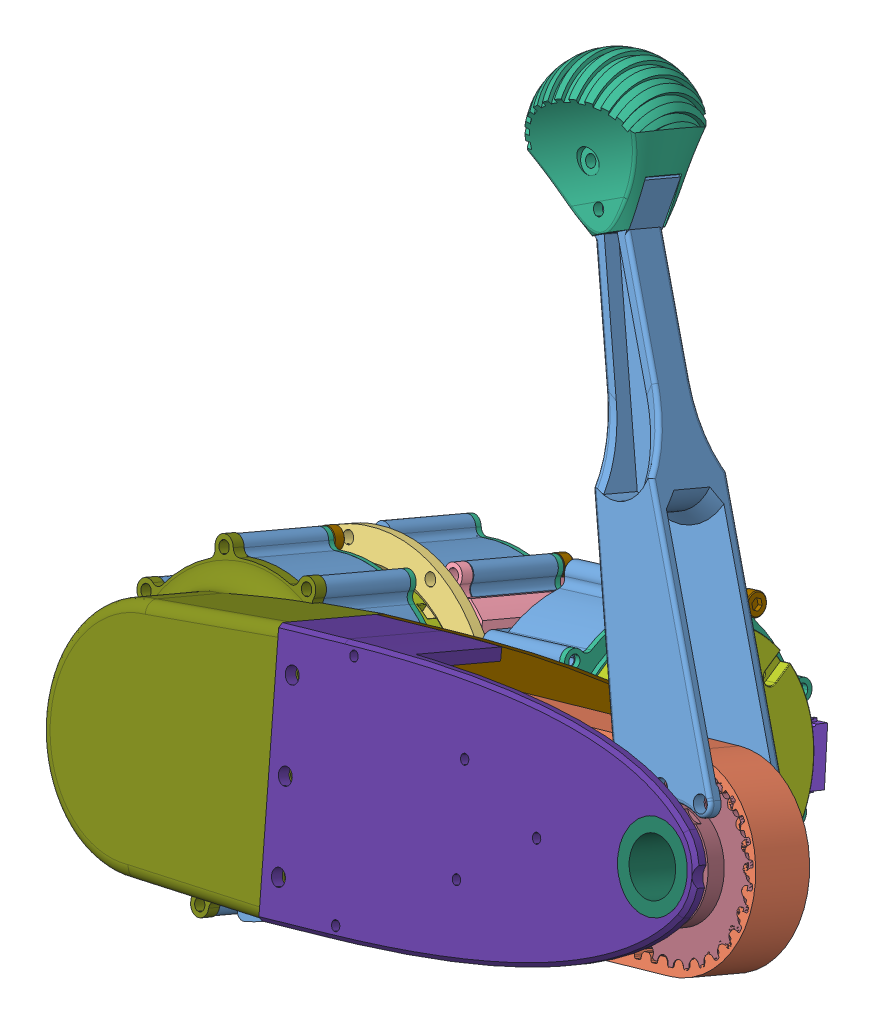
SolidWorks assembly 机械腿装配体, configuration 默认. Lengths in mm.
Overall size (235.81 267.44 159.84).
76 component instances, 24 part files, 46 mates.
Components (placement in the parent):
- CyberGearmotor.stp-1: CyberGearmotor.stp [默认] at (-32.9062 325.199 163.8526) x (0.625011 -0.709591 0.325334) z (0.103003 -0.338154 -0.935437) size (96.28 96.17 36.5)
  - ASM0002_ASM_1_ASM.stp-1: ASM0002_ASM_1_ASM.stp [默认] at origin size (96.28 96.17 36.5)
    - ASM0002_ASM_1_ASM_1_ASM.stp-1: ASM0002_ASM_1_ASM_1_ASM.stp [默认] at origin size (96.28 96.17 36.5)
      - 0714_ASM_1_ASM_1_ASM_1_ASM.stp-1: 0714_ASM_1_ASM_1_ASM_1_ASM.stp [默认] at origin size (96.28 96.17 36.5)
        - 3_1_02_067_0003_ASM_ASM_1_ASM_1_ASM.stp-1: 3_1_02_067_0003_ASM_ASM_1_ASM_1_ASM.stp [默认] at origin size (96.28 96.17 36.5)
          - 3_1_02_067_0003_ASM_1_ASM_1_ASM_ASM.stp-1: 3_1_02_067_0003_ASM_1_ASM_1_ASM_ASM.stp [默认] at origin size (96.28 96.17 36.5)
            - 1_1_06_EB673-504_1_1_1_1_1.stp-1: 1_1_06_EB673-504_1_1_1_1_1.stp [默认] at (39.8324 39.833 -22) size (79.19 78.95 25.5)
            - 1_2_04_670601_1_1_1_1_1.stp-1: 1_2_04_670601_1_1_1_1_1.stp [默认] at (93.9161 79.9966 -44) size (37 37 4)
            - 1_1_02_EB671-500_1_1_1_1_1.stp-1: 1_1_02_EB671-500_1_1_1_1_1.stp [默认] at (93.9161 79.9966 -44.4) x (-0.960973 0.276644 0) z (0 0 1) size (33 33 8.5)
            - 1_2_04_694000_1_1_1_1_1.stp-1: 1_2_04_694000_1_1_1_1_1.stp [默认] at (93.9161 79.9966 -44.5) size (11 11 4)
            - 1_2_06_000213_1_1_1_1_1.stp-1: 1_2_06_000213_1_1_1_1_1.stp [默认] at (93.9161 79.9966 -45.5) size (38.8 36.2 1.5)
            - 1_1_31_QT-642_1_1_1_1_1.stp-1: 1_1_31_QT-642_1_1_1_1_1.stp [默认] at (93.9161 79.9966 -22) x (-0.970555 -0.24088 0) z (0 0 -1) size (79.5 79.36 6)
            - 1_1_06_EB673-502_1_1_1_1_1.stp-1: 1_1_06_EB673-502_1_1_1_1_1.stp [默认] at (93.9161 79.9966 -13) x (-0.515958 -0.856614 0) z (0 0 -1) size (63 63 8)
          - 0518_ASM_2_ASM_1_ASM_1_ASM_1_AS_ASM.stp-1: 0518_ASM_2_ASM_1_ASM_1_ASM_1_AS_ASM.stp [默认] at (93.9161 79.9966 -17.235) x (0.235897 -0.971778 0) z (0 0 1) size (15.5 11.3 5.2)
            - 12345_ASM_1_ASM_2_ASM_1_ASM_1_A_ASM.stp-1: 12345_ASM_1_ASM_2_ASM_1_ASM_1_A_ASM.stp [默认] at origin size (15.5 11.3 5.2)
              - DUANZI_1_3_1_1_1_1_1_1.stp-1: DUANZI_1_3_1_1_1_1_1_1.stp [默认] at (-0.1798 16.5474 0.4329) x (0 0 -1) z (0 1 0) size (5.2 15.5 11.3)
      - LUODING_1_1.stp-1: LUODING_1_1.stp [默认] at (119.9375 52.9941 -20.5) x (-1 0 0) z (0 1 0) size (5.68 3 5.68)
      - LUODING_1_1.stp-2: LUODING_1_1.stp [默认] at (104.2902 116.0331 -20.5) x (-1 0 0) z (0 1 0) size (5.68 3 5.68)
      - LUODING_1_1.stp-3: LUODING_1_1.stp [默认] at (57.5205 70.9626 -20.5) x (-1 0 0) z (0 1 0) size (5.68 3 5.68)
  - 0411-2_4_1_3_1.stp-1: 0411-2_4_1_3_1.stp [默认] at (93.9161 79.9964 -17.5) x (0.235904 -0.971776 0) z (0 0 1) size (58 56.68 1.62)
- 带轮-1: 带轮 [默认] at (-43.0537 231.9338 268.6088) x (-0.773277 0.564305 -0.28914) z (0.103003 -0.338154 -0.935437) size (43.22 43.22 15)
- 带轮挡边-1: 带轮挡边 [默认] at (-41.5159 226.8587 254.5775) x (-0.77368 0.56382 -0.289009) z (0.103003 -0.338154 -0.935437) size (50 50 4)
- 带轮挡边-2: 带轮挡边 [默认] at (-43.4729 233.2836 272.3508) x (-0.154553 -0.934458 0.320782) z (0.103003 -0.338154 -0.935437) size (50 50 4)
- 膝关节带轮-1: 膝关节带轮 [默认] at (87.8678 264.231 271.3497) x (-0.849589 -0.51899 0.094061) z (0.103003 -0.338154 -0.935437) size (43.22 43.22 23)
- 轴承-1: 轴承 [默认] at (108.6723 269.1151 252.0981) x (-0.628078 -0.751354 0.20245) z (-0.103003 0.338154 0.935437) size (23 23 4)
- 轴承-2: 轴承 [默认] at (106.7153 275.54 269.8714) x (0.986125 -0.08837 0.14053) z (-0.103003 0.338154 0.935437) size (23 23 4)
- 膝关节转轴-1: 膝关节转轴 [默认] at (108.9298 268.2697 249.7595) x (-0.975627 0.148845 -0.161235) z (-0.103003 0.338154 0.935437) size (21 21 29)
- 大腿根部SLDPRT-3: 大腿根部SLDPRT [默认] at (-114.7317 234.0313 236.4395) x (-0.869822 -0.486803 0.080198) z (-0.103003 0.338154 0.935437) size (94.61 80.08 30.19)
- 大腿前部-1: 大腿前部 [默认] at (32.2959 248.9567 279.3042) x (0.25876 -0.89895 0.353457) z (0.960434 0.278461 0.005094) size (62 27.01 128.98)
- 大腿前部盖子-1: 大腿前部盖子 [默认] at (31.2591 253.1493 245.6039) x (-0.25876 0.89895 -0.353457) z (0.960434 0.278461 0.005094) size (62 3.5 129)
- 小腿2-1: 小腿2 [默认] at (74.1718 322.5647 235.3916) x (-0.51729 0.785048 -0.34075) z (0.849589 0.51899 -0.094061) size (141.69 21.45 28.63)
- 5m同步带1-1: 5m同步带1 [默认] at (106.5885 272.5591 262.3829) x (-0.103003 0.338154 0.935437) z (0.960434 0.278461 0.005094) size (15 46.9 201.91)
- 连接盘-1: 连接盘 [默认] at (-37.4901 211.9018 211.7872) x (-0.928292 -0.370496 0.031715) z (-0.3573 0.865092 -0.352068) size (80.5 13.5 80.5)
- CyberGearmotor.stp-2: CyberGearmotor.stp [默认] at (47.9911 286 142.5663) x (-0.002703 -0.940531 0.339698) z (0.103003 -0.338154 -0.935437) size (96.28 96.17 36.5)
  - ASM0002_ASM_1_ASM.stp-1: ASM0002_ASM_1_ASM.stp [默认] at origin size (96.28 96.17 36.5)
    - ASM0002_ASM_1_ASM_1_ASM.stp-1: ASM0002_ASM_1_ASM_1_ASM.stp [默认] at origin size (96.28 96.17 36.5)
      - 0714_ASM_1_ASM_1_ASM_1_ASM.stp-1: 0714_ASM_1_ASM_1_ASM_1_ASM.stp [默认] at origin size (96.28 96.17 36.5)
        - 3_1_02_067_0003_ASM_ASM_1_ASM_1_ASM.stp-1: 3_1_02_067_0003_ASM_ASM_1_ASM_1_ASM.stp [默认] at origin size (96.28 96.17 36.5)
          - 3_1_02_067_0003_ASM_1_ASM_1_ASM_ASM.stp-1: 3_1_02_067_0003_ASM_1_ASM_1_ASM_ASM.stp [默认] at origin size (96.28 96.17 36.5)
            - 1_1_06_EB673-504_1_1_1_1_1.stp-1: 1_1_06_EB673-504_1_1_1_1_1.stp [默认] at (39.8324 39.833 -22) size (79.19 78.95 25.5)
            - 1_2_04_670601_1_1_1_1_1.stp-1: 1_2_04_670601_1_1_1_1_1.stp [默认] at (93.9161 79.9966 -44) size (37 37 4)
            - 1_1_02_EB671-500_1_1_1_1_1.stp-1: 1_1_02_EB671-500_1_1_1_1_1.stp [默认] at (93.9161 79.9966 -44.4) x (-0.960973 0.276644 0) z (0 0 1) size (33 33 8.5)
            - 1_2_04_694000_1_1_1_1_1.stp-1: 1_2_04_694000_1_1_1_1_1.stp [默认] at (93.9161 79.9966 -44.5) size (11 11 4)
            - 1_2_06_000213_1_1_1_1_1.stp-1: 1_2_06_000213_1_1_1_1_1.stp [默认] at (93.9161 79.9966 -45.5) size (38.8 36.2 1.5)
            - 1_1_31_QT-642_1_1_1_1_1.stp-1: 1_1_31_QT-642_1_1_1_1_1.stp [默认] at (93.9161 79.9966 -22) x (-0.970555 -0.24088 0) z (0 0 -1) size (79.5 79.36 6)
            - 1_1_06_EB673-502_1_1_1_1_1.stp-1: 1_1_06_EB673-502_1_1_1_1_1.stp [默认] at (93.9161 79.9966 -13) x (-0.515958 -0.856614 0) z (0 0 -1) size (63 63 8)
          - 0518_ASM_2_ASM_1_ASM_1_ASM_1_AS_ASM.stp-1: 0518_ASM_2_ASM_1_ASM_1_ASM_1_AS_ASM.stp [默认] at (93.9161 79.9966 -17.235) x (0.235897 -0.971778 0) z (0 0 1) size (15.5 11.3 5.2)
            - 12345_ASM_1_ASM_2_ASM_1_ASM_1_A_ASM.stp-1: 12345_ASM_1_ASM_2_ASM_1_ASM_1_A_ASM.stp [默认] at origin size (15.5 11.3 5.2)
              - DUANZI_1_3_1_1_1_1_1_1.stp-1: DUANZI_1_3_1_1_1_1_1_1.stp [默认] at (-0.1798 16.5474 0.4329) x (0 0 -1) z (0 1 0) size (5.2 15.5 11.3)
      - LUODING_1_1.stp-1: LUODING_1_1.stp [默认] at (119.9375 52.9941 -20.5) x (-1 0 0) z (0 1 0) size (5.68 3 5.68)
      - LUODING_1_1.stp-2: LUODING_1_1.stp [默认] at (104.2902 116.0331 -20.5) x (-1 0 0) z (0 1 0) size (5.68 3 5.68)
      - LUODING_1_1.stp-3: LUODING_1_1.stp [默认] at (57.5205 70.9626 -20.5) x (-1 0 0) z (0 1 0) size (5.68 3 5.68)
  - 0411-2_4_1_3_1.stp-1: 0411-2_4_1_3_1.stp [默认] at (93.9161 79.9964 -17.5) x (0.235904 -0.971776 0) z (0 0 1) size (58 56.68 1.62)
- 肩关节连接器-1: 肩关节连接器 [默认] at (-3.9141 154.2094 236.5535) x (-0.002729 -0.940532 0.339695) z (0.994677 0.032437 0.097801) size (67.92 36.71 40.7)
- CyberGearmotor.stp-3: CyberGearmotor.stp [默认] at (56.3683 218.9179 320.1116) x (0.161386 -0.529819 -0.832614) z (0.956605 0.291387 0) size (96.28 96.17 36.5)
  - ASM0002_ASM_1_ASM.stp-1: ASM0002_ASM_1_ASM.stp [默认] at origin size (96.28 96.17 36.5)
    - ASM0002_ASM_1_ASM_1_ASM.stp-1: ASM0002_ASM_1_ASM_1_ASM.stp [默认] at origin size (96.28 96.17 36.5)
      - 0714_ASM_1_ASM_1_ASM_1_ASM.stp-1: 0714_ASM_1_ASM_1_ASM_1_ASM.stp [默认] at origin size (96.28 96.17 36.5)
        - 3_1_02_067_0003_ASM_ASM_1_ASM_1_ASM.stp-1: 3_1_02_067_0003_ASM_ASM_1_ASM_1_ASM.stp [默认] at origin size (96.28 96.17 36.5)
          - 3_1_02_067_0003_ASM_1_ASM_1_ASM_ASM.stp-1: 3_1_02_067_0003_ASM_1_ASM_1_ASM_ASM.stp [默认] at origin size (96.28 96.17 36.5)
            - 1_1_06_EB673-504_1_1_1_1_1.stp-1: 1_1_06_EB673-504_1_1_1_1_1.stp [默认] at (39.8324 39.833 -22) size (79.19 78.95 25.5)
            - 1_2_04_670601_1_1_1_1_1.stp-1: 1_2_04_670601_1_1_1_1_1.stp [默认] at (93.9161 79.9966 -44) size (37 37 4)
            - 1_1_02_EB671-500_1_1_1_1_1.stp-1: 1_1_02_EB671-500_1_1_1_1_1.stp [默认] at (93.9161 79.9966 -44.4) x (-0.960973 0.276644 0) z (0 0 1) size (33 33 8.5)
            - 1_2_04_694000_1_1_1_1_1.stp-1: 1_2_04_694000_1_1_1_1_1.stp [默认] at (93.9161 79.9966 -44.5) size (11 11 4)
            - 1_2_06_000213_1_1_1_1_1.stp-1: 1_2_06_000213_1_1_1_1_1.stp [默认] at (93.9161 79.9966 -45.5) size (38.8 36.2 1.5)
            - 1_1_31_QT-642_1_1_1_1_1.stp-1: 1_1_31_QT-642_1_1_1_1_1.stp [默认] at (93.9161 79.9966 -22) x (-0.970555 -0.24088 0) z (0 0 -1) size (79.5 79.36 6)
            - 1_1_06_EB673-502_1_1_1_1_1.stp-1: 1_1_06_EB673-502_1_1_1_1_1.stp [默认] at (93.9161 79.9966 -13) x (-0.515958 -0.856614 0) z (0 0 -1) size (63 63 8)
          - 0518_ASM_2_ASM_1_ASM_1_ASM_1_AS_ASM.stp-1: 0518_ASM_2_ASM_1_ASM_1_ASM_1_AS_ASM.stp [默认] at (93.9161 79.9966 -17.235) x (0.235897 -0.971778 0) z (0 0 1) size (15.5 11.3 5.2)
            - 12345_ASM_1_ASM_2_ASM_1_ASM_1_A_ASM.stp-1: 12345_ASM_1_ASM_2_ASM_1_ASM_1_A_ASM.stp [默认] at origin size (15.5 11.3 5.2)
              - DUANZI_1_3_1_1_1_1_1_1.stp-1: DUANZI_1_3_1_1_1_1_1_1.stp [默认] at (-0.1798 16.5474 0.4329) x (0 0 -1) z (0 1 0) size (5.2 15.5 11.3)
      - LUODING_1_1.stp-1: LUODING_1_1.stp [默认] at (119.9375 52.9941 -20.5) x (-1 0 0) z (0 1 0) size (5.68 3 5.68)
      - LUODING_1_1.stp-2: LUODING_1_1.stp [默认] at (104.2902 116.0331 -20.5) x (-1 0 0) z (0 1 0) size (5.68 3 5.68)
      - LUODING_1_1.stp-3: LUODING_1_1.stp [默认] at (57.5205 70.9626 -20.5) x (-1 0 0) z (0 1 0) size (5.68 3 5.68)
  - 0411-2_4_1_3_1.stp-1: 0411-2_4_1_3_1.stp [默认] at (93.9161 79.9964 -17.5) x (0.235904 -0.971776 0) z (0 0 1) size (58 56.68 1.62)
- 大腿根部线束限位扣-1: 大腿根部线束限位扣 [默认] at (9.8494 240.149 247.9459) x (-0.25876 0.89895 -0.353457) z (-0.960434 -0.278461 -0.005094) size (22 6 10)
- 狗jio-1: 狗jio [默认] at (30.4631 389.807 211.6162) x (0.849589 0.51899 -0.094061) z (0.103003 -0.338154 -0.935437) size (38.01 39.33 33.29)
Mates (geometry in assembly coordinates):
- 同心1: concentric aligned: cylinder of CyberGearmotor.stp-1/ASM0002_ASM_1_ASM.stp-1/ASM0002_ASM_1_ASM_1_ASM.stp-1/0714_ASM_1_ASM_1_ASM_1_ASM.stp-1/3_1_02_067_0003_ASM_ASM_1_ASM_1_ASM.stp-1/3_1_02_067_0003_ASM_1_ASM_1_ASM_ASM.stp-1/1_1_02_EB671-500_1_1_1_1_1.stp-1 through (-40.6815 224.1196 247.0004) axis (-0.103003 0.338154 0.935437) radius 16.5; cylinder of 带轮挡边-1 through (-41.1039 225.506 250.8357) axis (-0.103003 0.338154 0.935437) radius 25
- 重合1: coincident anti-aligned: plane of CyberGearmotor.stp-1/ASM0002_ASM_1_ASM.stp-1/ASM0002_ASM_1_ASM_1_ASM.stp-1/0714_ASM_1_ASM_1_ASM_1_ASM.stp-1/3_1_02_067_0003_ASM_ASM_1_ASM_1_ASM.stp-1/3_1_02_067_0003_ASM_1_ASM_1_ASM_ASM.stp-1/1_1_02_EB671-500_1_1_1_1_1.stp-1 through (-41.1039 225.506 250.8357) normal (-0.103003 0.338154 0.935437); plane of 带轮挡边-1 through (-41.1039 225.506 250.8357) normal (0.103003 -0.338154 -0.935437)
- 重合4: coincident anti-aligned: plane of 带轮-1 through (-30.3993 244.2236 249.5242) normal (0.103003 -0.338154 -0.935437); plane of 带轮挡边-1 through (-41.5159 226.8587 254.5775) normal (-0.103003 0.338154 0.935437)
- 同心12: concentric aligned: cylinder of CyberGearmotor.stp-1/ASM0002_ASM_1_ASM.stp-1/ASM0002_ASM_1_ASM_1_ASM.stp-1/0714_ASM_1_ASM_1_ASM_1_ASM.stp-1/3_1_02_067_0003_ASM_ASM_1_ASM_1_ASM.stp-1/3_1_02_067_0003_ASM_1_ASM_1_ASM_ASM.stp-1/1_1_02_EB671-500_1_1_1_1_1.stp-1 through (-40.6815 224.1196 247.0004) axis (-0.103003 0.338154 0.935437) radius 16.5; cylinder of 带轮挡边-2 through (-43.0609 231.931 268.609) axis (-0.103003 0.338154 0.935437) radius 25
- 重合5: coincident anti-aligned: plane of 带轮-1 through (-31.9444 249.2959 263.5558) normal (-0.103003 0.338154 0.935437); plane of 带轮挡边-2 through (-43.0609 231.931 268.609) normal (0.103003 -0.338154 -0.935437)
- 同心20: concentric aligned: cylinder of 轴承-1 through (108.2603 270.4677 255.8398) axis (0.103003 -0.338154 -0.935437) radius 8.5; cylinder of 膝关节转轴-1 through (106.0457 277.738 275.9517) axis (0.103003 -0.338154 -0.935437) radius 8.5
- 重合12: coincident anti-aligned: plane of CyberGearmotor.stp-1/ASM0002_ASM_1_ASM.stp-1/ASM0002_ASM_1_ASM_1_ASM.stp-1/0714_ASM_1_ASM_1_ASM_1_ASM.stp-1/3_1_02_067_0003_ASM_ASM_1_ASM_1_ASM.stp-1/3_1_02_067_0003_ASM_1_ASM_1_ASM_ASM.stp-1/1_1_06_EB673-504_1_1_1_1_1.stp-1 through (-39.9814 224.5982 248.0804) normal (-0.103003 0.338154 0.935437); plane of 大腿根部SLDPRT-3 through (-114.7317 234.0313 236.4395) normal (0.103003 -0.338154 -0.935437)
- 重合17: coincident anti-aligned: plane of 大腿根部SLDPRT-3 through (-3.7839 276.1352 262.2995) normal (-0.103003 0.338154 0.935437); plane of 大腿前部-1 through (32.6049 247.9422 276.4979) normal (0.103003 -0.338154 -0.935437)
- 重合18: coincident anti-aligned: plane of 大腿根部SLDPRT-3 through (-10.6072 264.2204 236.9917) normal (0.960434 0.278461 0.005094); plane of 大腿前部-1 through (-3.0951 237.5916 276.3086) normal (-0.960434 -0.278461 -0.005094)
- 重合21: coincident anti-aligned: plane of 大腿根部SLDPRT-3 through (14.4721 213.244 258.1809) normal (0.25876 -0.89895 0.353457); plane of 大腿前部-1 through (40.2588 221.8245 261.1256) normal (-0.25876 0.89895 -0.353457)
- 同心32: concentric anti-aligned: cylinder of 膝关节转轴-1 through (106.0457 277.738 275.9517) axis (0.103003 -0.338154 -0.935437) radius 8.5; cylinder of 大腿前部-1 through (106.2518 277.0617 274.0809) axis (-0.103003 0.338154 0.935437) radius 8.5
- 重合23: coincident aligned: plane of 膝关节转轴-1 through (105.9427 278.0762 276.8872) normal (-0.103003 0.338154 0.935437); plane of 大腿前部-1 through (32.2959 248.9567 279.3042) normal (-0.103003 0.338154 0.935437)
- 重合32: coincident anti-aligned: plane of 带轮挡边-1 through (-41.5159 226.8587 254.5775) normal (-0.103003 0.338154 0.935437); plane of 5m同步带1-1 through (102.2769 287.6855 248.4224) normal (0.103003 -0.338154 -0.935437)
- 同心44: concentric aligned: cylinder of 带轮挡边-1 through (-41.1039 225.506 250.8357) axis (-0.103003 0.338154 0.935437) radius 25; cylinder of 5m同步带1-1 through (-42.2884 229.3948 261.5932) axis (-0.103003 0.338154 0.935437) radius 23.448
- 同心47: concentric anti-aligned: cylinder of 膝关节带轮-1 through (108.3118 270.2986 255.3721) axis (-0.103003 0.338154 0.935437) radius 10.5; cylinder of 膝关节转轴-1 through (106.0457 277.738 275.9517) axis (0.103003 -0.338154 -0.935437) radius 8.5
- 重合38: coincident anti-aligned: plane of 带轮-1 through (-30.3993 244.2236 249.5242) normal (0.103003 -0.338154 -0.935437); plane of 带轮挡边-1 through (-41.5159 226.8587 254.5775) normal (-0.103003 0.338154 0.935437)
- 重合39: coincident aligned: plane of 带轮-1 through (-31.9444 249.2959 263.5558) normal (-0.103003 0.338154 0.935437); plane of 膝关节带轮-1 through (93.6077 290.474 262.495) normal (-0.103003 0.338154 0.935437)
- 重合41: coincident anti-aligned: plane of 膝关节带轮-1 through (108.2333 270.5153 255.8197) normal (0.103003 -0.338154 -0.935437); plane of 轴承-1 through (108.2603 270.4677 255.8398) normal (-0.103003 0.338154 0.935437)
- 重合42: coincident anti-aligned: plane of 膝关节带轮-1 through (93.6077 290.474 262.495) normal (-0.103003 0.338154 0.935437); plane of 小腿2-1 through (72.8843 326.7916 247.0846) normal (0.103003 -0.338154 -0.935437)
- 同心50: concentric aligned: cylinder of 膝关节带轮-1 through (112.0714 285.0521 250.4528) axis (0.103003 -0.338154 -0.935437) radius 1.65; cylinder of 小腿2-1 through (107.2302 300.9454 294.4183) axis (0.103003 -0.338154 -0.935437) radius 2.1
- 同心51: concentric aligned: cylinder of 膝关节带轮-1 through (100.0352 282.8594 249.9201) axis (0.103003 -0.338154 -0.935437) radius 1.65; cylinder of 小腿2-1 through (95.194 298.7526 293.8857) axis (0.103003 -0.338154 -0.935437) radius 2.1
- 同心53: concentric aligned: circle of 轴承-2; cylinder of 膝关节转轴-1 through (108.4148 269.9605 254.4367) axis (-0.103003 0.338154 0.935437) radius 7
- 重合44: coincident anti-aligned: plane of 大腿根部SLDPRT-3 through (-1.3118 268.0195 239.849) normal (0.103003 -0.338154 -0.935437); plane of 大腿前部盖子-1 through (30.9501 254.1637 248.4102) normal (-0.103003 0.338154 0.935437)
- 同心54: concentric anti-aligned: cylinder of 大腿根部SLDPRT-3 through (-5.7904 265.0304 266.0928) axis (-0.103003 0.338154 0.935437) radius 1.65; cylinder of 大腿前部盖子-1 through (-3.3183 256.9147 243.6423) axis (0.103003 -0.338154 -0.935437) radius 2.1
- 同心55: concentric anti-aligned: cylinder of 大腿根部SLDPRT-3 through (5.0776 227.2745 280.938) axis (-0.103003 0.338154 0.935437) radius 1.65; cylinder of 大腿前部盖子-1 through (7.5496 219.1588 258.4875) axis (0.103003 -0.338154 -0.935437) radius 2.1
- 重合45: coincident anti-aligned: plane of CyberGearmotor.stp-1/ASM0002_ASM_1_ASM.stp-1/ASM0002_ASM_1_ASM_1_ASM.stp-1/0714_ASM_1_ASM_1_ASM_1_ASM.stp-1/3_1_02_067_0003_ASM_ASM_1_ASM_1_ASM.stp-1/3_1_02_067_0003_ASM_1_ASM_1_ASM_ASM.stp-1/1_1_06_EB673-502_1_1_1_1_1.stp-1 through (-37.3442 213.1634 216.6923) normal (0.103003 -0.338154 -0.935437); plane of 连接盘-1 through (-38.0051 213.5926 216.4644) normal (-0.103003 0.338154 0.935437)
- 同心56: concentric aligned: cylinder of CyberGearmotor.stp-1/ASM0002_ASM_1_ASM.stp-1/ASM0002_ASM_1_ASM_1_ASM.stp-1/0714_ASM_1_ASM_1_ASM_1_ASM.stp-1/3_1_02_067_0003_ASM_ASM_1_ASM_1_ASM.stp-1/3_1_02_067_0003_ASM_1_ASM_1_ASM_ASM.stp-1/1_1_06_EB673-502_1_1_1_1_1.stp-1 through (-38.1683 215.8686 224.1758) axis (0.103003 -0.338154 -0.935437) radius 31.5; cylinder of 连接盘-1 through (-37.3442 213.1634 216.6923) axis (0.103003 -0.338154 -0.935437) radius 40.25
- 同心57: concentric aligned: cylinder of CyberGearmotor.stp-1/ASM0002_ASM_1_ASM.stp-1/ASM0002_ASM_1_ASM_1_ASM.stp-1/0714_ASM_1_ASM_1_ASM_1_ASM.stp-1/3_1_02_067_0003_ASM_ASM_1_ASM_1_ASM.stp-1/3_1_02_067_0003_ASM_1_ASM_1_ASM_ASM.stp-1/1_1_31_QT-642_1_1_1_1_1.stp-1 through (-28.5595 250.441 213.2706) axis (0.103003 -0.338154 -0.935437) radius 1.55; cylinder of 连接盘-1 through (-27.684 247.5667 205.3194) axis (0.103003 -0.338154 -0.935437) radius 1.6
- 同心61: concentric aligned: cylinder of CyberGearmotor.stp-1/ASM0002_ASM_1_ASM.stp-1/ASM0002_ASM_1_ASM_1_ASM.stp-1/0714_ASM_1_ASM_1_ASM_1_ASM.stp-1/3_1_02_067_0003_ASM_ASM_1_ASM_1_ASM.stp-1/3_1_02_067_0003_ASM_1_ASM_1_ASM_ASM.stp-1/1_1_06_EB673-502_1_1_1_1_1.stp-1 through (-38.1683 215.8686 224.1758) axis (0.103003 -0.338154 -0.935437) radius 31.5; cylinder of CyberGearmotor.stp-2/ASM0002_ASM_1_ASM.stp-1/ASM0002_ASM_1_ASM_1_ASM.stp-1/0714_ASM_1_ASM_1_ASM_1_ASM.stp-1/3_1_02_067_0003_ASM_ASM_1_ASM_1_ASM.stp-1/3_1_02_067_0003_ASM_1_ASM_1_ASM_ASM.stp-1/1_1_06_EB673-502_1_1_1_1_1.stp-1 through (-33.8936 201.8353 185.3551) axis (0.103003 -0.338154 -0.935437) radius 31.5
- 重合48: coincident anti-aligned: plane of 连接盘-1 through (-37.4901 211.9018 211.7872) normal (0.103003 -0.338154 -0.935437); plane of CyberGearmotor.stp-2/ASM0002_ASM_1_ASM.stp-1/ASM0002_ASM_1_ASM_1_ASM.stp-1/0714_ASM_1_ASM_1_ASM_1_ASM.stp-1/3_1_02_067_0003_ASM_ASM_1_ASM_1_ASM.stp-1/3_1_02_067_0003_ASM_1_ASM_1_ASM_ASM.stp-1/1_1_02_EB671-500_1_1_1_1_1.stp-1 through (-36.8292 211.4726 212.0151) normal (-0.103003 0.338154 0.935437)
- 同心70: concentric anti-aligned: cylinder of CyberGearmotor.stp-2/ASM0002_ASM_1_ASM.stp-1/ASM0002_ASM_1_ASM_1_ASM.stp-1/0714_ASM_1_ASM_1_ASM_1_ASM.stp-1/3_1_02_067_0003_ASM_ASM_1_ASM_1_ASM.stp-1/3_1_02_067_0003_ASM_1_ASM_1_ASM_ASM.stp-1/1_1_31_QT-642_1_1_1_1_1.stp-1 through (-33.9451 202.0043 185.8228) axis (0.103003 -0.338154 -0.935437) radius 32; cylinder of 肩关节连接器-1 through (-33.6361 200.9899 183.0165) axis (-0.103003 0.338154 0.935437) radius 32
- 重合51: coincident anti-aligned: plane of CyberGearmotor.stp-2/ASM0002_ASM_1_ASM.stp-1/ASM0002_ASM_1_ASM_1_ASM.stp-1/0714_ASM_1_ASM_1_ASM_1_ASM.stp-1/3_1_02_067_0003_ASM_ASM_1_ASM_1_ASM.stp-1/3_1_02_067_0003_ASM_1_ASM_1_ASM_ASM.stp-1/1_1_31_QT-642_1_1_1_1_1.stp-1 through (-33.9451 202.0043 185.8228) normal (0.103003 -0.338154 -0.935437); plane of 肩关节连接器-1 through (-1.0094 144.6735 210.1742) normal (-0.103003 0.338154 0.935437)
- 同心71: concentric aligned: cylinder of CyberGearmotor.stp-2/ASM0002_ASM_1_ASM.stp-1/ASM0002_ASM_1_ASM_1_ASM.stp-1/0714_ASM_1_ASM_1_ASM_1_ASM.stp-1/3_1_02_067_0003_ASM_ASM_1_ASM_1_ASM.stp-1/3_1_02_067_0003_ASM_1_ASM_1_ASM_ASM.stp-1/1_1_06_EB673-504_1_1_1_1_1.stp-1 through (-3.8379 224.0977 182.2525) axis (-0.103003 0.338154 0.935437) radius 1.25; cylinder of 肩关节连接器-1 through (-1.1773 215.3632 158.0902) axis (-0.103003 0.338154 0.935437) radius 1.6
- 重合52: coincident anti-aligned: plane of 肩关节连接器-1 through (22.8915 162.3745 236.5535) normal (0.956605 0.291387 0); plane of CyberGearmotor.stp-3/ASM0002_ASM_1_ASM.stp-1/ASM0002_ASM_1_ASM_1_ASM.stp-1/0714_ASM_1_ASM_1_ASM_1_ASM.stp-1/3_1_02_067_0003_ASM_ASM_1_ASM_1_ASM.stp-1/3_1_02_067_0003_ASM_1_ASM_1_ASM_ASM.stp-1/1_1_02_EB671-500_1_1_1_1_1.stp-1 through (5.7214 218.743 197.6094) normal (-0.956605 -0.291387 0)
- 同心72: concentric anti-aligned: cylinder of 肩关节连接器-1 through (-37.8855 205.4601 197.6094) axis (0.956605 0.291387 0) radius 21; cylinder of CyberGearmotor.stp-3/ASM0002_ASM_1_ASM.stp-1/ASM0002_ASM_1_ASM_1_ASM.stp-1/0714_ASM_1_ASM_1_ASM_1_ASM.stp-1/3_1_02_067_0003_ASM_ASM_1_ASM_1_ASM.stp-1/3_1_02_067_0003_ASM_1_ASM_1_ASM_ASM.stp-1/1_1_02_EB671-500_1_1_1_1_1.stp-1 through (9.6435 219.9377 197.6094) axis (-0.956605 -0.291387 0) radius 16.5
- 同心87: concentric aligned: cylinder of CyberGearmotor.stp-1/ASM0002_ASM_1_ASM.stp-1/ASM0002_ASM_1_ASM_1_ASM.stp-1/0714_ASM_1_ASM_1_ASM_1_ASM.stp-1/3_1_02_067_0003_ASM_ASM_1_ASM_1_ASM.stp-1/3_1_02_067_0003_ASM_1_ASM_1_ASM_ASM.stp-1/1_1_06_EB673-504_1_1_1_1_1.stp-1 through (-41.0172 225.2216 250.049) axis (0.103003 -0.338154 -0.935437) radius 21.5; cylinder of 大腿根部SLDPRT-3 through (-43.8849 234.6362 276.0925) axis (0.103003 -0.338154 -0.935437) radius 29
- 同心90: concentric aligned: cylinder of 带轮-1 through (-38.7715 221.5506 272.8338) axis (-0.103003 0.338154 0.935437) radius 2.05; cylinder of 带轮挡边-2 through (-38.1535 219.5217 267.2211) axis (-0.103003 0.338154 0.935437) radius 2.05
- 同心91: concentric aligned: cylinder of 带轮-1 through (-38.7715 221.5506 272.8338) axis (-0.103003 0.338154 0.935437) radius 2.05; cylinder of 带轮挡边-1 through (-36.1964 213.0967 249.4478) axis (-0.103003 0.338154 0.935437) radius 2.05
- 重合55: coincident anti-aligned: plane of 膝关节带轮-1 through (106.6883 275.5876 269.8512) normal (-0.103003 0.338154 0.935437); plane of 轴承-2 through (106.7153 275.54 269.8714) normal (0.103003 -0.338154 -0.935437)
- 平行2: parallel aligned: plane of 大腿前部-1 through (22.5199 282.9783 262.7221) normal (-0.25876 0.89895 -0.353457); plane of 5m同步带1-1 through (101.2936 291.1015 247.0792) normal (-0.25876 0.89895 -0.353457)
- 重合58: coincident anti-aligned: plane of 大腿前部盖子-1 through (31.2591 253.1493 245.6039) normal (0.103003 -0.338154 -0.935437); plane of 大腿根部线束限位扣-1 through (9.8494 240.149 247.9459) normal (-0.103003 0.338154 0.935437)
- 同心92: concentric aligned: cylinder of 大腿前部盖子-1 through (7.7793 247.3406 245.1183) axis (0.103003 -0.338154 -0.935437) radius 1.25; cylinder of 大腿根部线束限位扣-1 through (7.3673 248.6932 248.86) axis (0.103003 -0.338154 -0.935437) radius 1.55
- 同心93: concentric aligned: cylinder of 大腿前部盖子-1 through (11.9195 232.9574 250.7736) axis (0.103003 -0.338154 -0.935437) radius 1.25; cylinder of 大腿根部线束限位扣-1 through (11.5075 234.31 254.5153) axis (0.103003 -0.338154 -0.935437) radius 1.55
- 重合64: coincident anti-aligned: plane of 小腿2-1 through (29.4308 392.2828 215.9526) normal (-0.51729 0.785048 -0.34075); plane of 狗jio-1 through (29.9458 390.592 211.2754) normal (0.51729 -0.785048 0.34075)
- 重合65: coincident anti-aligned: plane of 小腿2-1 through (73.1418 325.9462 244.746) normal (-0.103003 0.338154 0.935437); plane of 狗jio-1 through (17.6119 374.0525 221.2413) normal (0.103003 -0.338154 -0.935437)
- 重合66: coincident anti-aligned: plane of 小腿2-1 through (68.8939 323.3513 245.2163) normal (-0.849589 -0.51899 0.094061); plane of 狗jio-1 through (25.6979 387.9971 211.7457) normal (0.849589 0.51899 -0.094061)
